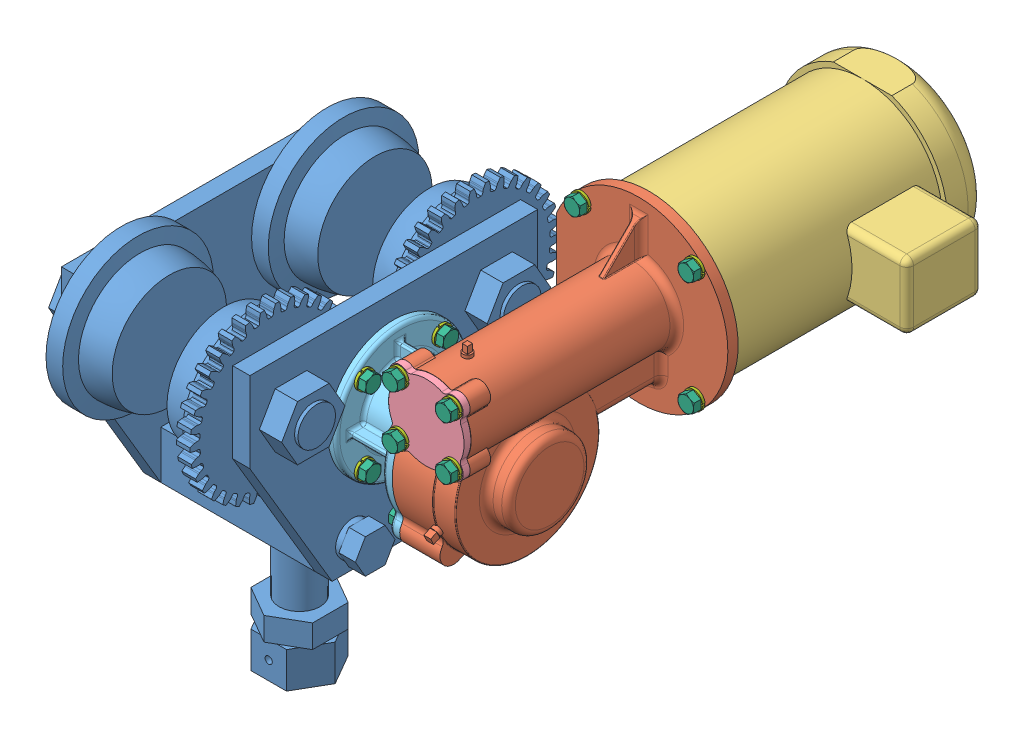
SolidWorks assembly M2631B-RH, configuration Default. Lengths in mm.
Overall size (426.15 413.65 540.72).
40 component instances, 7 part files, 3 mates.
Components (placement in the parent):
- Copy of M2631B-TROLLEY- SECTION^M2631B-RH-1: Copy of M2631B-TROLLEY- SECTION^M2631B-RH [S8x18.4#] at origin size (222.38 375.83 342.81) (virtual)
- Copy of SDT GEAR REDUCER TEMPLATE^M2631B-RH-1: Copy of SDT GEAR REDUCER TEMPLATE^M2631B-RH [Default] at (190.5 120.2538 0) size (229.23 225.42 451.54) (virtual)
  - Copy of P423 TEMPLATE^Copy of SDT GEAR REDUCER TEMPLATE_M2631B-RH-1: Copy of P423 TEMPLATE^Copy of SDT GEAR REDUCER TEMPLATE_M2631B-RH [Default] at (0 66.675 -133.35) x (1 0 0) z (0 0 -1) size (158.75 225.42 205.51) (virtual)
  - Copy of DE175^Copy of SDT GEAR REDUCER TEMPLATE_M2631B-RH-1: Copy of DE175^Copy of SDT GEAR REDUCER TEMPLATE_M2631B-RH [Default] at (0 66.675 -133.35) x (-1 0 0) z (0 0 1) size (203.07 152.4 235.97) (virtual)
  - Copy of K960^Copy of SDT GEAR REDUCER TEMPLATE_M2631B-RH-1: Copy of K960^Copy of SDT GEAR REDUCER TEMPLATE_M2631B-RH [Default] at (0 66.675 66.675) size (69.85 69.85 6.35) (virtual)
  - Copy of M2872 TEMPLATE^Copy of SDT GEAR REDUCER TEMPLATE_M2631B-RH-1: Copy of M2872 TEMPLATE^Copy of SDT GEAR REDUCER TEMPLATE_M2631B-RH [Default] at (-104.775 0 0) x (0 0 -1) z (1 0 0) size (133.35 133.35 67.47) (virtual)
  - hex bolt_ai-17: hex bolt_ai [HBOLT 0.3125-18x0.3125x0.3125-N] at (-54.7814 -47.1463 -47.1463) size (13.91 14.66 12.7)
  - hex bolt_ai-16: hex bolt_ai [HBOLT 0.3125-18x0.3125x0.3125-N] at (-54.7814 -47.1463 47.1463) size (13.91 14.66 12.7)
  - hex bolt_ai-15: hex bolt_ai [HBOLT 0.3125-18x0.3125x0.3125-N] at (-54.7814 47.1463 -47.1463) size (13.91 14.66 12.7)
  - hex bolt_ai-14: hex bolt_ai [HBOLT 0.3125-18x0.3125x0.3125-N] at (-54.7814 47.1463 47.1463) size (13.91 14.66 12.7)
  - hex bolt_ai-13: hex bolt_ai [HBOLT 0.3750-16x0.375x0.375-N] at (-86.0552 35.921 -35.921) x (-1 0 0) z (0 0.924225 0.381849) size (16.33 16.48 14.27)
  - hex bolt_ai-12: hex bolt_ai [HBOLT 0.3750-16x0.375x0.375-N] at (-86.0552 -35.921 -35.921) x (-1 0 0) z (0 0.924225 0.381849) size (16.33 16.48 14.27)
  - hex bolt_ai-11: hex bolt_ai [HBOLT 0.3750-16x0.375x0.375-N] at (-86.0552 35.921 35.921) x (-1 0 0) z (0 0.924225 0.381849) size (16.33 16.48 14.27)
  - hex bolt_ai-10: hex bolt_ai [HBOLT 0.3750-16x0.375x0.375-N] at (-86.0552 -35.921 35.921) x (-1 0 0) z (0 0.924225 0.381849) size (16.33 16.48 14.27)
  - hex bolt_ai-9: hex bolt_ai [HBOLT 0.3750-16x0.375x0.375-N] at (-24.6957 41.9793 82.2198) x (0 0 -1) z (1 0 0) size (16.33 16.48 14.27)
  - hex bolt_ai-8: hex bolt_ai [HBOLT 0.3750-16x0.375x0.375-N] at (24.6957 41.9793 82.2198) x (0 0 -1) z (1 0 0) size (16.33 16.48 14.27)
  - hex bolt_ai-7: hex bolt_ai [HBOLT 0.3750-16x0.375x0.375-N] at (24.6957 91.3707 82.2198) x (0 0 -1) z (1 0 0) size (16.33 16.48 14.27)
  - hex bolt_ai-6: hex bolt_ai [HBOLT 0.3750-16x0.375x0.375-N] at (-24.6957 91.3707 82.2198) x (0 0 -1) z (1 0 0) size (16.33 16.48 14.27)
  - hex bolt_ai-5: hex bolt_ai [HBOLT 0.3750-16x0.375x0.375-N] at (-52.759 13.916 -114.6226) x (0 0 -1) z (1 0 0) size (16.33 16.48 14.27)
  - hex bolt_ai-4: hex bolt_ai [HBOLT 0.3750-16x0.375x0.375-N] at (52.759 13.916 -114.6226) x (0 0 -1) z (1 0 0) size (16.33 16.48 14.27)
  - hex bolt_ai-3: hex bolt_ai [HBOLT 0.3750-16x0.375x0.375-N] at (52.759 119.434 -114.6226) x (0 0 -1) z (1 0 0) size (16.33 16.48 14.27)
  - hex bolt_ai-2: hex bolt_ai [HBOLT 0.3750-16x0.375x0.375-N] at (-13.9415 85.7087 -162.1812) size (16.33 16.48 14.27)
  - hex bolt_ai-1: hex bolt_ai [HBOLT 0.3750-16x0.375x0.375-N] at (-52.759 119.434 -114.6226) x (0 0 -1) z (1 0 0) size (16.33 16.48 14.27)
  - lock washer spring regular_ai-28: lock washer spring regular_ai [Regular LW 0.375] at (-52.759 13.916 -123.8174) x (0 0 -1) z (1 0 0) size (2.39 17.35 17.32)
  - lock washer spring regular_ai-27: lock washer spring regular_ai [Regular LW 0.375] at (52.759 13.916 -123.8174) x (0 0 -1) z (1 0 0) size (2.39 17.35 17.32)
  - lock washer spring regular_ai-26: lock washer spring regular_ai [Regular LW 0.375] at (27.7844 13.3346 -154.6583) size (2.39 17.35 17.32)
  - lock washer spring regular_ai-25: lock washer spring regular_ai [Regular LW 0.375] at (52.759 119.434 -123.8174) x (0 0 -1) z (1 0 0) size (2.39 17.35 17.32)
  - lock washer spring regular_ai-24: lock washer spring regular_ai [Regular LW 0.375] at (-52.759 119.434 -123.8174) x (0 0 -1) z (1 0 0) size (2.39 17.35 17.32)
  - lock washer spring regular_ai-23: lock washer spring regular_ai [Regular LW 0.375] at (-95.25 35.921 -35.921) x (-1 0 0) z (0 0.924225 0.381849) size (2.39 17.35 17.32)
  - lock washer spring regular_ai-22: lock washer spring regular_ai [Regular LW 0.375] at (-95.25 -35.921 -35.921) x (-1 0 0) z (0 0.924225 0.381849) size (2.39 17.35 17.32)
  - lock washer spring regular_ai-21: lock washer spring regular_ai [Regular LW 0.375] at (-95.25 -35.921 35.921) x (-1 0 0) z (0 0.924225 0.381849) size (2.39 17.35 17.32)
  - lock washer spring regular_ai-20: lock washer spring regular_ai [Regular LW 0.375] at (-95.25 35.921 35.921) x (-1 0 0) z (0 0.924225 0.381849) size (2.39 17.35 17.32)
  - lock washer spring regular_ai-19: lock washer spring regular_ai [Regular LW 0.375] at (24.6957 91.3707 73.025) x (0 0 -1) z (1 0 0) size (2.39 17.35 17.32)
  - lock washer spring regular_ai-18: lock washer spring regular_ai [Regular LW 0.375] at (24.6957 41.9793 73.025) x (0 0 -1) z (1 0 0) size (2.39 17.35 17.32)
  - lock washer spring regular_ai-17: lock washer spring regular_ai [Regular LW 0.375] at (-24.6957 41.9793 73.025) x (0 0 -1) z (1 0 0) size (2.39 17.35 17.32)
  - lock washer spring regular_ai-16: lock washer spring regular_ai [Regular LW 0.375] at (-24.6957 91.3707 73.025) x (0 0 -1) z (1 0 0) size (2.39 17.35 17.32)
  - lock washer spring regular_ai-15: lock washer spring regular_ai [Regular LW 0.3125] at (-46.8312 47.1463 47.1463) size (1.98 14.88 14.86)
  - lock washer spring regular_ai-14: lock washer spring regular_ai [Regular LW 0.3125] at (-46.8312 -47.1463 -47.1463) size (1.98 14.88 14.86)
  - lock washer spring regular_ai-13: lock washer spring regular_ai [Regular LW 0.3125] at (-46.8312 -47.1463 47.1463) size (1.98 14.88 14.86)
  - lock washer spring regular_ai-11: lock washer spring regular_ai [Regular LW 0.3125] at (-46.8312 47.1463 -47.1463) size (1.98 14.88 14.86)
Mates (geometry in assembly coordinates):
- Coincident1: coincident aligned: plane of Copy of M2631B-TROLLEY- SECTION^M2631B-RH-1 through (0 120.2538 0) normal (0 1 0); plane of Copy of SDT GEAR REDUCER TEMPLATE^M2631B-RH-1 through (190.5 120.2538 0) normal (0 1 0)
- Coincident2: coincident aligned: plane of Copy of M2631B-TROLLEY- SECTION^M2631B-RH-1 through (0 0 0) normal (0 0 1); plane of Copy of SDT GEAR REDUCER TEMPLATE^M2631B-RH-1 through (190.5 120.2538 0) normal (0 0 1)
- Distance2: distance = 14.2875 mm aligned: plane of Copy of M2631B-TROLLEY- SECTION^M2631B-RH-1 through (71.4375 0 -133.35) normal (-1 0 0); plane of Copy of SDT GEAR REDUCER TEMPLATE^M2631B-RH-1/Copy of M2872 TEMPLATE^Copy of SDT GEAR REDUCER TEMPLATE_M2631B-RH-1 through (85.725 120.2538 0) normal (-1 0 0)
